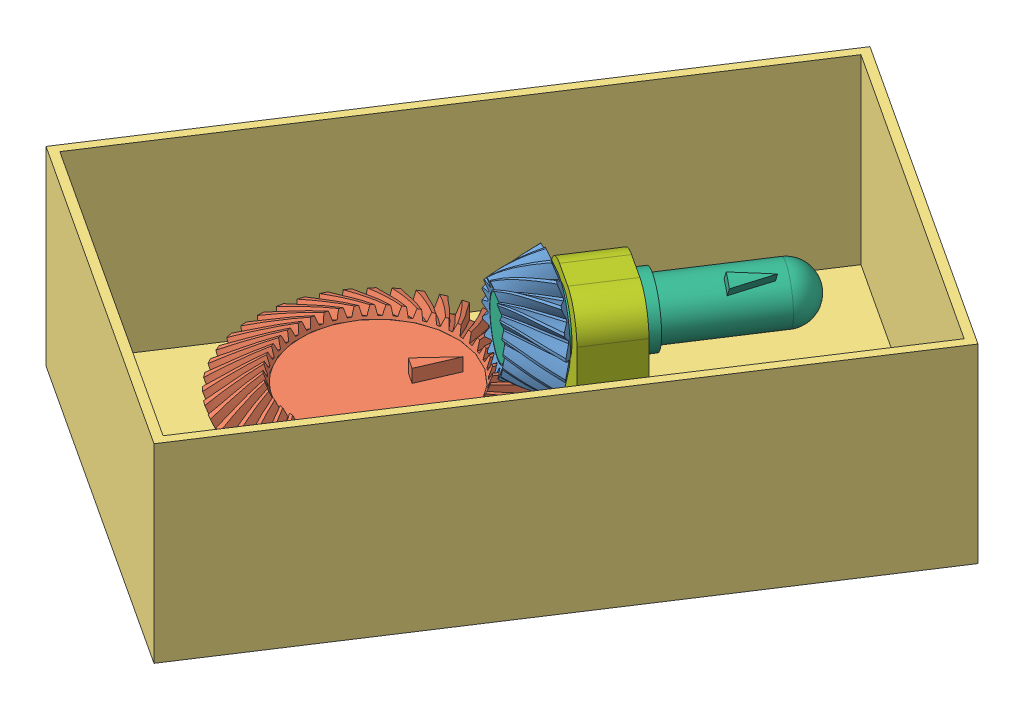
SolidWorks assembly bevelgear_det_ass_mm_4LFQ4, configuration Default. Lengths in mm.
Overall size (398.98 212.06 384.99).
8 component instances, 7 part files, 9 mates.
Components (placement in the parent):
- bevelgear_det_pinion_mm_4LFQ4-1: bevelgear_det_pinion_mm_4LFQ4 [Default] at (-89.1942 228.6732 220.0646) x (0.546944 0 -0.837169) z (-0.837169 0 -0.546944) size (127.18 184.96 121.42)
- bevelgear_det_wheel_mm_4LFQ4-1: bevelgear_det_wheel_mm_4LFQ4 [Default] at (34.5873 342.445 24.6582) x (0 -1 0) z (0.546944 0 -0.837169) size (86.43 370.32 99.55)
- Basic-ForSizing-1: Basic-ForSizing [Default] at (62.4988 183.1732 -45.4624) x (0.837169 0 0.546944) z (-0.546944 0 0.837169) size (142.88 73.02 228.6)
- stepper_holder_flat-1: stepper_holder_flat [Default] at (23.1115 244.3375 81.095) x (-0.837169 0 -0.546944) z (0 -1 0) size (42 61 29.32)
  - Step Motor (28BYJ-48)-1: Step Motor (28BYJ-48) [Varsayılan] at (21.2606 45.5238 45.0393) size (42 61 29.02)
  - stepper_holder_28BYJ-48-flat-1: stepper_holder_28BYJ-48-flat [Default] at (20.4592 39.4575 43.5393) x (1 0 0) z (0 -1 0) size (42 20.8 25)
- shaft-1: shaft [Default] at (55.0853 228.6732 -0.7738) x (0.700852 -0.546944 0.457885) z (0.457885 0.837169 0.299148) size (24 90 27)
- piston_holder-1: piston_holder [Default] at (70.0803 183.1732 -25.8551) x (0.837169 0 0.546944) z (-0.546944 0 0.837169) size (35 60.5 20)
Mates (geometry in assembly coordinates):
- Coincident3: coincident aligned: plane of Basic-ForSizing-1 through (62.4988 179.9982 -45.4624) normal (0 -1 0); plane of stepper_holder_flat-1/stepper_holder_28BYJ-48-flat-1 through (30.1683 179.9982 31.422) normal (0 -1 0)
- Parallel1: parallel aligned: plane of Basic-ForSizing-1 through (-64.9255 253.0232 51.6718) normal (-0.546944 0 0.837169); plane of stepper_holder_flat-1/stepper_holder_28BYJ-48-flat-1 through (36.0114 199.2982 60.8735) normal (-0.546944 0 0.837169)
- Coincident7: coincident anti-aligned: plane of bevelgear_det_wheel_mm_4LFQ4-1 through (35.8598 211.2982 27.2813) normal (0.546944 0 -0.837169); plane of stepper_holder_flat-1/Step Motor (28BYJ-48)-1 through (32.0925 209.2982 24.8201) normal (-0.546944 0 0.837169)
- Coincident8: coincident: plane of bevelgear_det_wheel_mm_4LFQ4-1 through (35.8598 211.2982 27.2813) normal (-0.837169 0 -0.546944); moEndPointRef_w of stepper_holder_flat-1/Step Motor (28BYJ-48)-1
- Parallel2: parallel anti-aligned: plane of bevelgear_det_pinion_mm_4LFQ4-1 through (64.4249 213.6757 -15.0692) normal (0.546944 0 -0.837169); plane of Basic-ForSizing-1 through (58.3694 253.0232 -137.0471) normal (-0.546944 0 0.837169)
- Coincident10: coincident aligned: circle of bevelgear_det_pinion_mm_4LFQ4-1; circle of shaft-1
- Coincident11: coincident anti-aligned: plane of bevelgear_det_wheel_mm_4LFQ4-1 through (-2.8001 203.2982 0.2333) normal (0 -1 0); circle of stepper_holder_flat-1/Step Motor (28BYJ-48)-1
- Coincident12: coincident anti-aligned: plane of Basic-ForSizing-1 through (62.4988 183.1732 -45.4624) normal (0 1 0); plane of piston_holder-1 through (70.0803 183.1732 -25.8551) normal (0 -1 0)
- Perpendicular1: perpendicular: line of bevelgear_det_pinion_mm_4LFQ4-1 through (23.4323 228.6732 47.6753) axis (0.546944 0 -0.837169); line of piston_holder-1 through (90.7075 183.1732 -23.3023) axis (-0.837169 0 -0.546944)
